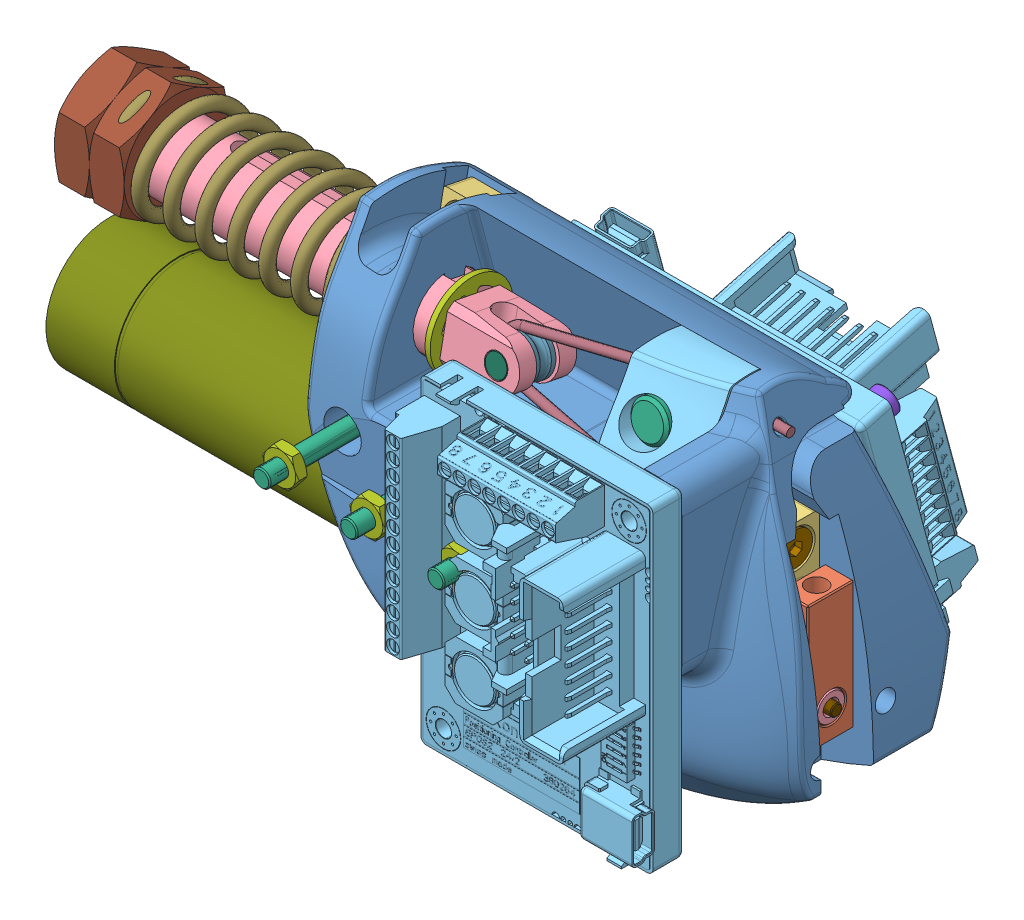
SolidWorks assembly a-antriebstrang-bein-rechts-v05, configuration Slave-BoardPosition 2. Lengths in mm.
Overall size (130.8 65.2 78.85).
43 component instances, 26 part files, 42 mates.
Components (placement in the parent):
- a-motorträger-beine-rechts-v01-1: a-motorträger-beine-rechts-v01 [01] x (-1 0 0) z (0 0 -1) size (130.38 65.2 41.28)
  - p-halterreferenz-rechts-v04-1: p-halterreferenz-rechts-v04 [01] at (-8 0 0) x (0 0 -1) z (1 0 0) size (41.28 65.2 84.36)
  - z-jfm-0608-06-v01-1: z-jfm-0608-06-v01 [01] at (-23.3 0 0) x (-1 0 0) z (0 0 -1) size (6 12 12)
  - z-induktiv-sensor-v01-1: z-induktiv-sensor-v01 [01] at (29 21.9082 7.6275) x (1 0 0) z (0 0.190809 -0.981627) size (8 16 4.7)
  - z-induktiv-sensor-v01-2: z-induktiv-sensor-v01 [01] at (-25.5 8.63 4) x (0 0 -1) z (-1 0 0) size (8 16 4.7)
  - p-federstössel-v01-1: p-federstössel-v01 [01] at (77.9 27.8 -1.72) x (-1 0 0) z (0 -0.190809 0.981627) size (77 12 12)
  - p-halterdeckel-rechts-v02-1: p-halterdeckel-rechts-v02 [01] at (-8 0 0) x (0 0 -1) z (1 0 0) size (28.27 33.45 14.71)
  - z-passschraube-misumi-4-v01-1: z-passschraube-misumi-4-v01 [01] at (-13.1 35.2829 -8.5672) x (0 -0.190809 0.981627) z (-0.839411 -0.533511 -0.103704) size (18 6.5 6.5)
  - z-passschraube-misumi-4-v01-2: z-passschraube-misumi-4-v01 [01] at (-13.1 16.1412 -12.288) x (0 -0.190809 0.981627) z (-0.58333 0.797312 0.154982) size (18 6.5 6.5)
  - Lock washer DIN 6799 - 7-11: Lock washer DIN 6799 - 7 [Lock washer DIN 6799 - 7] at (24 27.8 -1.72) x (0 0 1) z (-1 0 0) size (14.3 11.94 0.9)
  - Hexagon Nut ISO 4032 - M2.5 - W - N-19: Hexagon Nut ISO 4032 - M2.5 - W - N [Hexagon Nut ISO 4032 - M2.5 - W - N] at (-13.1 31.8991 8.8409) x (1 0 0) z (0 -0.190809 0.981627) size (5 5.77 2)
  - Hexagon Nut ISO 4032 - M2.5 - W - N-20: Hexagon Nut ISO 4032 - M2.5 - W - N [Hexagon Nut ISO 4032 - M2.5 - W - N] at (-13.1 12.7574 5.1202) x (1 0 0) z (0 -0.190809 0.981627) size (5 5.77 2)
  - DIN 7991 - M3 x 8 --- 4.8C-19: DIN 7991 - M3 x 8 --- 4.8C [DIN 7991 - M3 x 8 --- 4.8C] at (-30.15 20.63 0) size (8 5.7 5.7)
  - DIN 7991 - M3 x 8 --- 4.8C-20: DIN 7991 - M3 x 8 --- 4.8C [DIN 7991 - M3 x 8 --- 4.8C] at (33 34.5749 5.3527) x (0 -0.190809 0.981627) z (-0.981627 0.187303 0.036408) size (8 5.7 5.7)
  - p-oese-v01-1: p-oese-v01 [01] at (-25.5 37.4 0) size (3.5 4 4)
  - Hexagon Thin Nut ISO 4035 - M12 - N-19: Hexagon Thin Nut ISO 4035 - M12 - N [Hexagon Thin Nut ISO 4035 - M12 - N] at (74.9 27.8 -1.72) x (0 -0.006521 -0.999979) z (-1 0 0) size (18 20.78 6)
  - Hexagon Thin Nut ISO 4035 - M12 - N-20: Hexagon Thin Nut ISO 4035 - M12 - N [Hexagon Thin Nut ISO 4035 - M12 - N] at (80.9 27.8 -1.72) x (0 0 1) z (-1 0 0) size (18 20.78 6)
  - z-feder-febrotec-v01-1: z-feder-febrotec-v01 [01] at (40 28.171 -1.6479) x (1 0 0) z (0 -0.190809 0.981627) size (40.25 20.98 20.5)
  - p-seil-v02-1: p-seil-v02 [01] at (-16.85 -0.1381 -7.1506) x (-1 0 0) z (0 0.190809 -0.981627) size (48.5 39 1.5)
  - p-umlenkpulley-v06-1: p-umlenkpulley-v06 [01] at (-13.1 33.728 -0.5677) x (0 -0.190809 0.981627) z (-0.981627 0.187303 0.036408) size (3.6 7.15 7.15)
  - p-umlenkpulley-v06-4: p-umlenkpulley-v06 [01] at (-13.1 14.5863 -4.2885) x (0 -0.190809 0.981627) z (-0.997632 0.067518 0.013124) size (3.6 7.15 7.15)
  - p-umlenkpulley-v06-3: p-umlenkpulley-v06 [01] at (14.9 27.8 -1.72) x (0 -0.190809 0.981627) z (-0.981627 0.187303 0.036408) size (3.6 7.15 7.15)
  - Parallel Pin ISO 2338 - 4 h6 x 10 - St-11: Parallel Pin ISO 2338 - 4 h6 x 10 - St [Parallel Pin ISO 2338 - 4 h6 x 10 - St] at (14.9 28.754 -6.6281) x (0 -0.190809 0.981627) z (-0.981627 0.187303 0.036408) size (10 4 4)
- a-Maxon-EC22-386675-v01-2: a-Maxon-EC22-386675-v01 [01] at (-25.4 0 0) x (-1 0 0) z (0 0.342022 -0.939692) size (103.18 22 22)
  - z-Motor-Maxon-EC22-386673-v01-1: z-Motor-Maxon-EC22-386673-v01 [01] at origin size (73.23 22 22)
  - z-Getriebe-Maxon-GP22C_1-STUFIG-143972-v01-1: z-Getriebe-Maxon-GP22C_1-STUFIG-143972-v01 [01] at (-25.4 0 0) size (40.25 22 22)
- p-motorpulley-v04-2: p-motorpulley-v04 [01] at (3.15 0 0) x (1 0 0) z (0 0.939692 0.342022) size (35.05 9 9)
- DIN 913 - M2 x 3-C-10: DIN 913 - M2 x 3-C [DIN 913 - M2 x 3-C] at (10.15 4.2286 1.5391) x (0 -0.939692 -0.342022) z (1 0 0) size (3 2 2)
- p-absolutmess-plättchen-v04-2: p-absolutmess-plättchen-v04 [01] at (36.2 0 0) x (0 0 1) z (-1 0 0) size (8 22 5)
- ISO 2010 - M2.5 x 10 --- 10C-29: ISO 2010 - M2.5 x 10 --- 10C [ISO 2010 - M2.5 x 10 --- 10C] at (9 6.5778 2.3941) x (-1 0 0) z (0 -0.859497 -0.51114) size (10.59 4.7 4.66)
- ISO 2010 - M2.5 x 10 --- 10C-30: ISO 2010 - M2.5 x 10 --- 10C [ISO 2010 - M2.5 x 10 --- 10C] at (9 -5.3623 4.4995) x (-1 0 0) z (0 -0.924225 -0.381849) size (10.59 4.7 4.66)
- ISO 2010 - M2.5 x 10 --- 10C-31: ISO 2010 - M2.5 x 10 --- 10C [ISO 2010 - M2.5 x 10 --- 10C] at (9 -1.2155 -6.8937) x (-1 0 0) z (0 -0.959089 0.283105) size (10.59 4.7 4.66)
- p-gewindeeinsatz-v01-1: p-gewindeeinsatz-v01 [01] at (30.2 0 0) x (1 0 0) z (0 -0.998486 -0.054998) size (6 5 5)
- z-380264_epos2_24_2-v01-3: z-380264_epos2_24_2-v01 [01] at (9 10.5 22) x (0 1 0) z (1 0 0) size (55.21 20.01 40.39)
- z-380264_epos2_24_2-v01-2: z-380264_epos2_24_2-v01 [01] at (2 14.1149 -20.6087) x (1 0 0) z (0 0.965926 0.258819) size (55.21 20.01 40.39)
- z-zyl-schr-schaft-M3x40-v01-4: z-zyl-schr-schaft-M3x40-v01 [01] at (-2 15 -13) x (0 0 1) z (0.955009 0.296577 0) size (43 5.5 5.5)
- Hexagon Thin Nut ISO 4035 - M3 - C-11: Hexagon Thin Nut ISO 4035 - M3 - C [Hexagon Thin Nut ISO 4035 - M3 - C] at (-2 15 25) x (0.923728 0.383049 0) z (0 0 -1) size (5.5 6.35 1.8)
- z-zyl-schr-schaft-M3x40-v01-5: z-zyl-schr-schaft-M3x40-v01 [01] at (-17 15 -13) x (0 0 1) z (0.955009 0.296577 0) size (43 5.5 5.5)
- z-zyl-schr-schaft-M3x40-v01-6: z-zyl-schr-schaft-M3x40-v01 [01] at (-32 15 -13) x (0 0 1) z (0.955009 0.296577 0) size (43 5.5 5.5)
- Hexagon Thin Nut ISO 4035 - M3 - C-19: Hexagon Thin Nut ISO 4035 - M3 - C [Hexagon Thin Nut ISO 4035 - M3 - C] at (-17 15 25) x (0.923728 0.383049 0) z (0 0 -1) size (5.5 6.35 1.8)
- Hexagon Thin Nut ISO 4035 - M3 - C-20: Hexagon Thin Nut ISO 4035 - M3 - C [Hexagon Thin Nut ISO 4035 - M3 - C] at (-32 15 25) x (0.923728 0.383049 0) z (0 0 -1) size (5.5 6.35 1.8)
- n-zyl-schr-i6kt-M2.5x8 (BN11)-3: n-zyl-schr-i6kt-M2.5x8 (BN11) [n-zyl-schr-i6kt-M2.5x8 (BN11)] at (-21.5 -0.2788 -28.7101) x (0 -0.258819 0.965926) z (-0.965926 0.25 0.066987) size (10.5 4.5 4.5)
- n-zyl-schr-i6kt-M2.5x8 (BN11)-4: n-zyl-schr-i6kt-M2.5x8 (BN11) [n-zyl-schr-i6kt-M2.5x8 (BN11)] at (25.5 30.6309 -20.4279) x (0 -0.258819 0.965926) z (-0.793112 0.588322 0.15764) size (10.5 4.5 4.5)
Mates (geometry in assembly coordinates):
- Konzentrisch1: concentric aligned: cylinder of a-motorträger-beine-rechts-v01-1/p-halterreferenz-rechts-v04-1 through (0 0 0) axis (-1 0 0) radius 11.5; cylinder of a-Maxon-EC22-386675-v01-2/z-Getriebe-Maxon-GP22C_1-STUFIG-143972-v01-1 through (0 0 0) axis (-1 0 0) radius 11
- Deckungsgleich1: coincident anti-aligned: plane of a-motorträger-beine-rechts-v01-1/p-halterreferenz-rechts-v04-1 through (0 0 0) normal (-1 0 0); plane of a-Maxon-EC22-386675-v01-2/z-Getriebe-Maxon-GP22C_1-STUFIG-143972-v01-1 through (0 0 0) normal (1 0 0)
- Deckungsgleich2: coincident anti-aligned: plane of a-motorträger-beine-rechts-v01-1 through (0 0 0) normal (0 0 -1); plane of assembly through (0 0 0) normal (0 0 1)
- Deckungsgleich3: coincident aligned: plane of a-motorträger-beine-rechts-v01-1; plane of assembly through (0 0 0) normal (0 1 0)
- Deckungsgleich4: coincident anti-aligned: plane of a-motorträger-beine-rechts-v01-1 through (0 0 0) normal (-1 0 0); plane of assembly through (0 0 0) normal (1 0 0)
- Konzentrisch2: concentric aligned: cylinder of a-Maxon-EC22-386675-v01-2/z-Getriebe-Maxon-GP22C_1-STUFIG-143972-v01-1 through (14.85 0 0) axis (-1 0 0) radius 2; cylinder of p-motorpulley-v04-2 through (3.15 0 0) axis (-1 0 0) radius 2
- Deckungsgleich5: coincident anti-aligned: plane of a-Maxon-EC22-386675-v01-2/z-Getriebe-Maxon-GP22C_1-STUFIG-143972-v01-1 through (3.15 0 0) normal (1 0 0); plane of p-motorpulley-v04-2 through (3.15 1.5391 -4.2286) normal (-1 0 0)
- Konzentrisch3: concentric anti-aligned: cylinder of p-motorpulley-v04-2 through (10.15 0 0) axis (0 -0.939692 -0.342022) radius 0.8; cylinder of DIN 913 - M2 x 3-C-10 through (10.15 16.1627 5.8828) axis (0 0.939692 0.342022) radius 1
- Parallel2: parallel aligned: plane of a-Maxon-EC22-386675-v01-2/z-Getriebe-Maxon-GP22C_1-STUFIG-143972-v01-1 through (10.2 1.4095 0.513) normal (0 0.939692 0.342022); plane of p-motorpulley-v04-2 through (3.15 0 0) normal (0 0.939692 0.342022)
- Deckungsgleich7: coincident anti-aligned: plane of a-Maxon-EC22-386675-v01-2/z-Getriebe-Maxon-GP22C_1-STUFIG-143972-v01-1 through (10.2 1.4095 0.513) normal (0 0.939692 0.342022); plane of DIN 913 - M2 x 3-C-10 through (10.15 1.5805 0.0432) normal (0 -0.939692 -0.342022)
- Parallel3: parallel anti-aligned: plane of a-motorträger-beine-rechts-v01-1/p-halterreferenz-rechts-v04-1 through (42 0 -4.5) normal (0 0 1); plane of p-absolutmess-plättchen-v04-2 through (31.2 -5 -4) normal (0 0 -1)
- Abstand1: distance = 1 mm anti-aligned: plane of a-motorträger-beine-rechts-v01-1/z-induktiv-sensor-v01-2 through (30.2 8.63 -4) normal (1 0 0); plane of p-absolutmess-plättchen-v04-2 through (31.2 0 0) normal (-1 0 0)
- Konzentrisch5: concentric anti-aligned: cylinder of p-motorpulley-v04-2 through (3.15 0 0) axis (-1 0 0) radius 1; cylinder of p-absolutmess-plättchen-v04-2 through (31.2 0 0) axis (1 0 0) radius 2.5
- Konzentrisch6: concentric aligned: cylinder of a-motorträger-beine-rechts-v01-1/p-halterreferenz-rechts-v04-1 through (-42.3814 -5.3623 4.4995) axis (1 0 0) radius 1.5; cylinder of a-Maxon-EC22-386675-v01-2/z-Getriebe-Maxon-GP22C_1-STUFIG-143972-v01-1 through (-4 -5.3623 4.4995) axis (1 0 0) radius 1.025
- Konzentrisch29: concentric aligned: cylinder of a-motorträger-beine-rechts-v01-1/p-halterreferenz-rechts-v04-1 through (-42.3814 -5.3623 4.4995) axis (1 0 0) radius 1.5; cylinder of ISO 2010 - M2.5 x 10 --- 10C-30 through (24.875 -5.3623 4.4995) axis (1 0 0) radius 1.25
- Deckungsgleich16: coincident aligned: cone of a-motorträger-beine-rechts-v01-1/p-halterreferenz-rechts-v04-1 through (8 -5.3623 4.4995) axis (-1 0 0); cone of ISO 2010 - M2.5 x 10 --- 10C-30 through (8 -5.3623 4.4995) axis (-1 0 0)
- Konzentrisch31: concentric aligned: cylinder of a-motorträger-beine-rechts-v01-1/p-halterreferenz-rechts-v04-1 through (-42.3814 6.5778 2.3941) axis (1 0 0) radius 1.5; cylinder of ISO 2010 - M2.5 x 10 --- 10C-29 through (24.875 6.5778 2.3941) axis (1 0 0) radius 1.25
- Deckungsgleich17: coincident aligned: cone of a-motorträger-beine-rechts-v01-1/p-halterreferenz-rechts-v04-1 through (8 6.5778 2.3941) axis (-1 0 0); cone of ISO 2010 - M2.5 x 10 --- 10C-29 through (8 6.5778 2.3941) axis (-1 0 0)
- Konzentrisch33: concentric aligned: cylinder of a-motorträger-beine-rechts-v01-1/p-halterreferenz-rechts-v04-1 through (-42.3814 -1.2155 -6.8937) axis (1 0 0) radius 1.5; cylinder of ISO 2010 - M2.5 x 10 --- 10C-31 through (24.875 -1.2155 -6.8937) axis (1 0 0) radius 1.25
- Deckungsgleich18: coincident aligned: cone of a-motorträger-beine-rechts-v01-1/p-halterreferenz-rechts-v04-1 through (8 -1.2155 -6.8937) axis (-1 0 0); cone of ISO 2010 - M2.5 x 10 --- 10C-31 through (8 -1.2155 -6.8937) axis (-1 0 0)
- Konzentrisch318: concentric anti-aligned: cylinder of p-absolutmess-plättchen-v04-2 through (31.2 0 0) axis (1 0 0) radius 2.5; cylinder of p-gewindeeinsatz-v01-1 through (30.2 0 0) axis (-1 0 0) radius 2.5
- Deckungsgleich150: coincident aligned: plane of p-absolutmess-plättchen-v04-2 through (36.2 0 0) normal (1 0 0); plane of p-gewindeeinsatz-v01-1 through (36.2 -0.0275 0.4992) normal (1 0 0)
- Konzentrisch324: concentric anti-aligned: cylinder of a-motorträger-beine-rechts-v01-1/p-halterreferenz-rechts-v04-1 through (-2 15 -22.5327) axis (0 0 -1) radius 2; cylinder of z-zyl-schr-schaft-M3x40-v01-4 through (-2 15 12) axis (0 0 1) radius 1.5
- Deckungsgleich162: coincident anti-aligned: plane of a-motorträger-beine-rechts-v01-1/p-halterreferenz-rechts-v04-1 through (0 15 9) normal (0 0 1); plane of z-zyl-schr-schaft-M3x40-v01-4
- Konzentrisch325: concentric aligned: cylinder of z-zyl-schr-schaft-M3x40-v01-4 through (-2 15 -13) axis (0 0 -1) radius 1.5; cylinder of Hexagon Thin Nut ISO 4035 - M3 - C-11 through (-2 15 26.8) axis (0 0 -1) radius 1.25
- Abstand2: distance = 35 mm anti-aligned: plane of Hexagon Thin Nut ISO 4035 - M3 - C-11 through (-7.0805 12.8932 25) normal (0 0 -1); plane of z-zyl-schr-schaft-M3x40-v01-4 through (-1.1844 12.3737 -10) normal (0 0 1)
- Konzentrisch326: concentric aligned: cylinder of a-motorträger-beine-rechts-v01-1/p-halterreferenz-rechts-v04-1 through (-2 15 -22.5327) axis (0 0 -1) radius 2; cylinder of z-zyl-schr-schaft-M3x40-v01-4 through (-2 15 -13) axis (0 0 -1) radius 1.5
- Deckungsgleich163: coincident anti-aligned: plane of a-motorträger-beine-rechts-v01-1/p-halterreferenz-rechts-v04-1 through (1.25 15 -10) normal (0 0 -1); plane of z-zyl-schr-schaft-M3x40-v01-4 through (-1.1844 12.3737 -10) normal (0 0 1)
- Deckungsgleich165: coincident: plane of z-380264_epos2_24_2-v01-2 through (2 13.0796 -16.745) normal (0 -0.258819 0.965926); plane of a-motorträger-beine-rechts-v01-1/p-halterreferenz-rechts-v04-1 through (8 5.0624 -18.8932) normal (0 0.258819 -0.965926)
- Konzentrisch327: concentric: cylinder of a-motorträger-beine-rechts-v01-1/p-halterreferenz-rechts-v04-1 through (-21.5 -13.657 21.2181) axis (0 0.258819 -0.965926) radius 0.9; cylinder of z-380264_epos2_24_2-v01-2 through (-21.5 -0.9258 -26.2953) axis (0 0.258819 -0.965926) radius 1.35
- Konzentrisch328: concentric: cylinder of a-motorträger-beine-rechts-v01-1/p-halterreferenz-rechts-v04-1 through (25.5 26.2089 -3.9248) axis (0 0.258819 -0.965926) radius 0.9; cylinder of z-380264_epos2_24_2-v01-2 through (25.5 29.9838 -18.0131) axis (0 0.258819 -0.965926) radius 1.35
- Deckungsgleich166: coincident: plane of a-motorträger-beine-rechts-v01-1/p-halterreferenz-rechts-v04-1 through (28.5 37.5 18) normal (0 0 1); plane of z-380264_epos2_24_2-v01-3 through (9 10.5 18) normal (0 0 -1)
- Konzentrisch329: concentric: cylinder of a-motorträger-beine-rechts-v01-1/p-halterreferenz-rechts-v04-1 through (25 34 8) axis (0 0 1) radius 0.9; cylinder of z-380264_epos2_24_2-v01-3 through (25 34 23.6) axis (0 0 1) radius 1.35
- Konzentrisch330: concentric: cylinder of a-motorträger-beine-rechts-v01-1/p-halterreferenz-rechts-v04-1 through (-7 -13 8) axis (0 0 1) radius 0.9; cylinder of z-380264_epos2_24_2-v01-3 through (-7 -13 23.6) axis (0 0 1) radius 1.35
- Konzentrisch331: concentric: cylinder of z-380264_epos2_24_2-v01-2 through (25.5 29.9838 -18.0131) axis (0 0.258819 -0.965926) radius 1.35; cylinder of n-zyl-schr-i6kt-M2.5x8 (BN11)-4 through (25.5 38.8484 -51.0961) axis (0 0.258819 -0.965926) radius 1.25
- Deckungsgleich167: coincident: plane of z-380264_epos2_24_2-v01-2 through (25.5 29.9838 -18.0131) normal (0 0.258819 -0.965926); plane of n-zyl-schr-i6kt-M2.5x8 (BN11)-4 through (26.8704 31.7075 -17.5512) normal (0 -0.258819 0.965926)
- Konzentrisch332: concentric: cylinder of z-380264_epos2_24_2-v01-2 through (-21.5 -0.9258 -26.2953) axis (0 0.258819 -0.965926) radius 1.35; cylinder of n-zyl-schr-i6kt-M2.5x8 (BN11)-3 through (-21.5 7.9387 -59.3783) axis (0 0.258819 -0.965926) radius 1.25
- Deckungsgleich168: coincident: plane of z-380264_epos2_24_2-v01-2 through (-21.5 -0.9258 -26.2953) normal (0 0.258819 -0.965926); circle of n-zyl-schr-i6kt-M2.5x8 (BN11)-3
- Konzentrisch333: concentric: cylinder of z-380264_epos2_24_2-v01-3 through (-7 -13 23.6) axis (0 0 1) radius 1.35; cylinder of n-zyl-schr-i6kt-M2.5x8 (BN11)-3 through (-21.5 7.9387 -59.3783) axis (0 0.258819 -0.965926) radius 1.25
- Deckungsgleich169: coincident: plane of z-380264_epos2_24_2-v01-3 through (-7 -13 23.6) normal (0 0 1); plane of n-zyl-schr-i6kt-M2.5x8 (BN11)-3 through (-20.9177 1.1735 -25.7328) normal (0 -0.258819 0.965926)
- Konzentrisch334: concentric: cylinder of z-380264_epos2_24_2-v01-3 through (25 34 23.6) axis (0 0 1) radius 1.35; cylinder of n-zyl-schr-i6kt-M2.5x8 (BN11)-4 through (25.5 38.8484 -51.0961) axis (0 0.258819 -0.965926) radius 1.25
- Deckungsgleich170: coincident: plane of z-380264_epos2_24_2-v01-3 through (25 34 23.6) normal (0 0 1); plane of n-zyl-schr-i6kt-M2.5x8 (BN11)-4 through (26.8704 31.7075 -17.5512) normal (0 -0.258819 0.965926)
